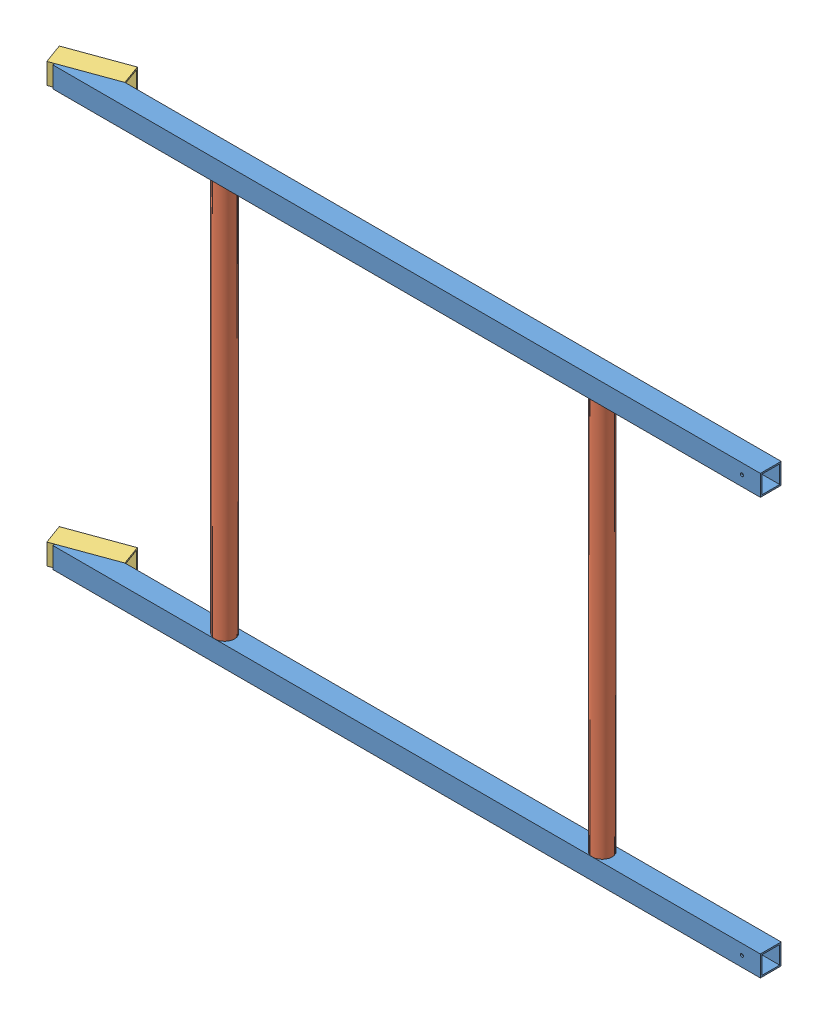
SolidWorks assembly GE-20201, configuration Default. Lengths in mm.
Overall size (1539.2 933.45 86.25).
6 component instances, 3 part files, 19 mates.
Components (placement in the parent):
- GE-20201-01-1: GE-20201-01 [Default] at (762 933.45 0) x (-1 0 0) z (0 0 1) size (1511.3 44.45 44.45)
- GE-20201-01-2: GE-20201-01 [Default] at (762 44.45 0) x (-1 0 0) z (0 0 1) size (1511.3 44.45 44.45)
- GE-20201-02-1: GE-20201-02 [Default] at (403.225 889 -21.082) x (-1 0 0) z (0 0 1) size (42.16 844.55 42.16)
- GE-20201-02-2: GE-20201-02 [Default] at (-403.225 889 -21.082) x (1 0 0) z (0 0 -1) size (42.16 844.55 42.16)
- GE-20201-03-1: GE-20201-03 [Default] at (-639.7949 44.45 -44.479) x (-0.939693 0 0.34202) z (0.34202 0 0.939693) size (130.05 44.45 44.45)
- GE-20201-03-2: GE-20201-03 [Default] at (-639.7949 933.45 -44.479) x (-0.939693 0 0.34202) z (0.34202 0 0.939693) size (130.05 44.45 44.45)
Mates (geometry in assembly coordinates):
- Coincident1: coincident anti-aligned: plane of GE-20201-01-1 through (-762 889 0) normal (0 -1 0); plane of GE-20310-02-1 through (623.443 889 -21.082) normal (0 1 0)
- Tangent1: tangent aligned: plane of GE-20201-01-1 through (-762 933.45 0) normal (0 0 1); cylinder of GE-20310-02-1 through (623.443 44.45 -21.082) axis (0 1 0) radius 21.082
- Tangent2: tangent aligned: plane of GE-20201-01-1 through (-762 933.45 0) normal (0 0 1); cylinder of GE-20310-02-2 through (-623.443 44.45 -21.082) axis (0 1 0) radius 21.082
- Coincident4: coincident anti-aligned: plane of GE-20201-01-1 through (-762 889 0) normal (0 -1 0); plane of GE-20310-02-2 through (-623.443 889 -21.082) normal (0 1 0)
- Tangent3: tangent aligned: plane of GE-20201-01-2 through (-762 44.45 0) normal (0 0 1); cylinder of GE-20310-02-1 through (623.443 44.45 -21.082) axis (0 1 0) radius 21.082
- Coincident6: coincident anti-aligned: plane of GE-20201-01-2 through (-762 44.45 0) normal (0 1 0); plane of GE-20310-02-1 through (623.443 44.45 -21.082) normal (0 -1 0)
- Coincident7: coincident anti-aligned: plane of GE-20201-01-1 through (-762 933.45 0) normal (-0.34202 0 -0.939693); plane of GE-20310-03-2 through (-762 933.45 0) normal (0.34202 0 0.939693)
- Coincident8: coincident aligned: plane of GE-20201-01-1 through (-762 889 0) normal (0 -1 0); plane of GE-20310-03-2 through (-762 889 0) normal (0 -1 0)
- Coincident9: coincident: plane of GE-20201-01-2 through (-762 44.45 0) normal (0 0 1); line of GE-20310-03-1 through (44.45 -762 0) axis (0 0 1)
- Coincident10: coincident anti-aligned: plane of GE-20201-01-2 through (-762 44.45 0) normal (-0.34202 0 -0.939693); plane of GE-20310-03-1 through (-762 44.45 0) normal (0.34202 0 0.939693)
- Coincident11: coincident aligned: plane of GE-20201-01-2 through (-762 0 0) normal (0 -1 0); plane of GE-20310-03-1 through (-762 0 0) normal (0 -1 0)
- Distance1: distance = 358.775 mm anti-aligned: plane of GE-20201-02-1 through (403.225 889 -21.082) normal (-1 0 0); plane of GE-20201-01-1 through (762 933.45 0) normal (1 0 0)
- Coincident14: coincident aligned: plane of GE-20201-01-1 through (762 933.45 0) normal (1 0 0); plane of GE-20201-01-2 through (762 44.45 0) normal (1 0 0)
- Coincident15: coincident aligned: plane of GE-20201-01-1 through (-762 933.45 0) normal (0 0 1)
- Symmetric1: symmetric aligned: plane of GE-20310-02-1 through (623.443 889 -21.082) normal (-1 0 0); plane of GE-20310-02-2 through (-623.443 889 -21.082) normal (1 0 0)
- Symmetric2: symmetric aligned: line of GE-20201-01-2 through (44.45 762 0) axis (0 0 1); line of GE-20310-03-1 through (44.45 -762 0) axis (0 0 1)
- Parallel1: parallel anti-aligned: plane of GE-20310-02-1 through (623.443 889 -21.082) normal (-1 0 0)
- Coincident17: coincident aligned: plane of GE-20310-03-1 through (-762 44.45 0) normal (-0.939693 0 0.34202); plane of GE-20310-03-2 through (-762 933.45 0) normal (-0.939693 0 0.34202)
- Coincident18: coincident anti-aligned: plane of GE-20201-01-2 through (-762 0 0) normal (0 -1 0)
